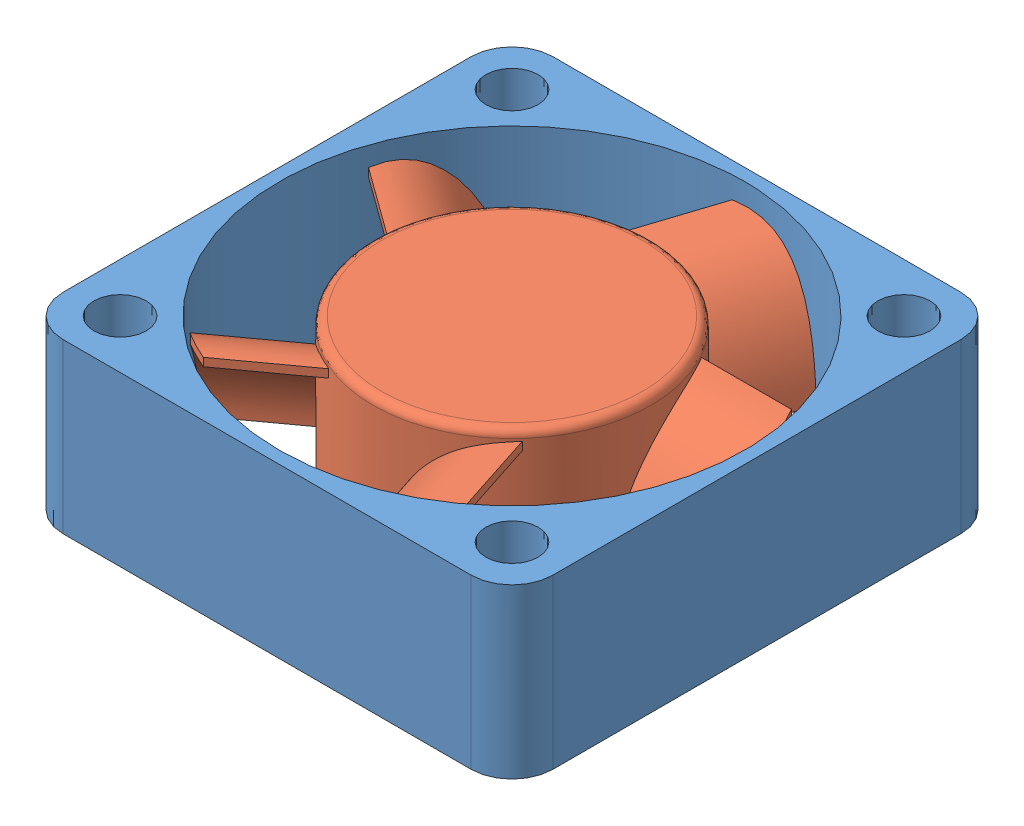
SolidWorks assembly 1313-Z1P-A, configuration Default. Lengths in mm.
Overall size (30 10.3 30).
2 component instances, 2 part files, 0 mates.
Components (placement in the parent):
- Fan Base 30x30-1: Fan Base 30x30 [Default] at (1.9775 7.6443 16.6801) size (30 10.3 30)
- Fan Rotor 30x30-1: Fan Rotor 30x30 [Default] at (1.9775 9.9443 16.6801) size (26.91 8.35 27.44)
